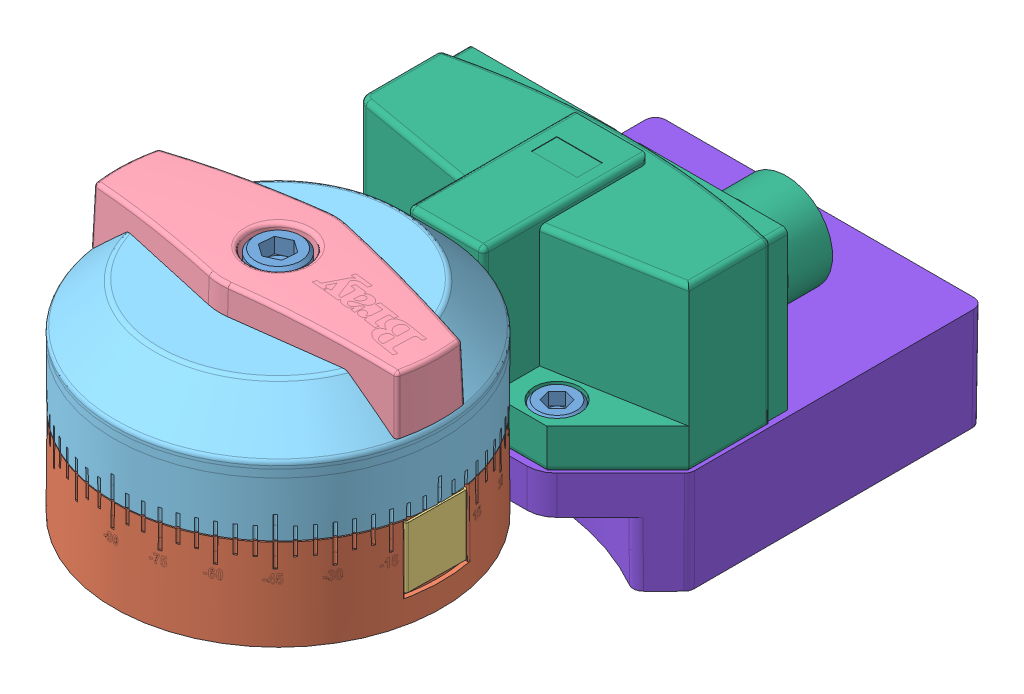
SolidWorks assembly SIZE 160-255, configuration Default. Lengths in mm.
Overall size (65.53 72.61 139.73).
13 component instances, 9 part files, 16 mates.
Components (placement in the parent):
- socket head cap screw_am-1: socket head cap screw_am [B18.3.1M - 5 x 0.8 x 12 Hex SHCS -- 12NHX] at (-500.171 31.6744 -463.7952) x (0 -1 0) z (-0.706848 0 0.707366) size (17 8.5 8.5)
- socket head cap screw_am-2: socket head cap screw_am [B18.3.1M - 5 x 0.8 x 12 Hex SHCS -- 12NHX] at (-470.1459 31.6744 -463.7952) x (0 -1 0) z (-0.706848 0 -0.707366) size (17 8.5 8.5)
- 54-000A-92510-1: 54-000A-92510 [Default] at (-485.1585 24.792 -423.7678) x (0.011705 0 -0.999931) z (0.999931 0 0.011705) size (64.81 35.64 64.77)
- 54-000A-73500-1: 54-000A-73500 [Default] at (-453.461 36.0489 -423.4339) x (0.011705 0 -0.999931) z (0.999931 0 0.011705) size (12.19 11.94 6.35)
- 54-000A-92512-1: 54-000A-92512 [Default] at (-485.1585 58.7518 -423.7678) x (-0.998952 0 -0.045767) z (0.045767 0 -0.998952) size (64.52 13.44 23.07)
- 54-000A-73500-2: 54-000A-73500 [Default] at (-484.8776 48.6153 -455.9616) x (-1 -0.000194 0.00096) z (-0.000958 -0.008727 -0.999961) size (12.19 11.94 6.35)
- 54-000A-92511-1: 54-000A-92511 [Default] at (-485.1585 42.8768 -423.7678) x (-0.999932 0 -0.011665) z (0.011665 0 -0.999932) size (64.76 21.97 66.01)
- 54-0004-71104-1: 54-0004-71104 [Default] at (-485.1732 23.6744 -492.2808) x (1 0 -0.000958) z (0.000958 0 1) size (65 33.5 50.77)
- 07-5623-72107-1: 07-5623-72107 [Default] at (-500.1471 20.3012 -488.7952) x (0 -1 0) z (0.643698 0 -0.76528) size (25 9.12 9.2)
- 07-5623-72107-2: 07-5623-72107 [Default] at (-470.1699 20.3012 -488.7952) x (0 -1 0) z (0.643698 0 0.76528) size (25 9.12 9.2)
- socket head cap screw_am-3: socket head cap screw_am [B18.3.1M - 6 x 1.0 x 30 Hex SHCS -- 30NHX] at (-485.1585 70.0858 -423.7678) x (0 -1 0) z (-0.995947 0 -0.089939) size (36 10 10)
- 54-160A-705S0-1: 54-160A-705S0 [Default] at (-485.2101 23.3696 -530.7098) x (-1 0 0.000958) z (-0.000958 0 -1) size (64.77 20.58 72.89)
- 54-160A-705P0-1: 54-160A-705P0 [Default] at (-485.1585 52.224 -423.7678) size (45.64 22.89 45.64)
Mates (geometry in assembly coordinates):
- Coincident1: coincident: plane of 54-000A-92510-1 through (-484.9073 52.224 -445.2293) normal (0 -1 0); plane of 54-160A-705P0-1 through (-485.1585 52.224 -423.7678) normal (0 1 0)
- Coincident2: coincident: plane of 54-000A-92510-1 through (-454.7314 24.792 -423.4117) normal (0.999931 0 0.011705); plane of 54-000A-73500-1 through (-454.6596 42.0179 -429.5444) normal (-0.999931 0 -0.011705)
- Parallel1: parallel: plane of 54-000A-73500-2 through (-478.7828 54.5853 -456.0195) normal (-0.000958 -0.008727 -0.999961); plane of 54-160A-705S0-1 through (-452.8251 23.3696 -530.7408) normal (-0.000958 -0.008727 -0.999961)
- Coincident3: coincident: line of 54-000A-73500-2 through (-490.9728 50.8497 -454.7052) axis (-0.000203 0.999962 -0.008726); plane of 54-000A-92511-1 through (-490.9626 42.8768 -454.2668) normal (0.99973 0 -0.023239)
- Coincident4: coincident: plane of 54-000A-92510-1 through (-485.0083 55.399 -436.5939) normal (0 1 0); plane of 54-000A-92511-1 through (-485.3053 55.399 -411.183) normal (0 -1 0)
- Parallel2: parallel: plane of 54-000A-92510-1 through (-454.8035 24.792 -417.2526) normal (0.046595 0 -0.998914); line of 54-000A-73500-1 through (-454.0657 30.0799 -417.3446) axis (0 1 0)
- Coincident5: coincident: plane of 54-000A-92512-1 through (-485.4102 64.0858 -418.2736) normal (0 1 0); plane of socket head cap screw_am-3 through (-485.6082 64.0858 -418.7881) normal (0 -1 0)
- Concentric1: concentric: cylinder of 54-000A-92510-1 through (-485.1585 15.4582 -423.7678) axis (0 1 0) radius 3.3; cylinder of 54-160A-705P0-1 through (-485.1585 61.5578 -423.7678) axis (0 -1 0) radius 3.3
- Concentric2: concentric: cylinder of 54-000A-92511-1 through (-485.1585 46.0652 -423.7678) axis (0 1 0) radius 3.3; cylinder of socket head cap screw_am-3 through (-485.1585 101.8358 -423.7678) axis (0 1 0) radius 3
- Concentric3: concentric: cylinder of 54-000A-92512-1 through (-485.1585 58.7518 -423.7678) axis (0 -1 0) radius 3.3; cylinder of 54-000A-92511-1 through (-485.1585 46.0652 -423.7678) axis (0 1 0) radius 3.3
- Distance1: distance = 0.1778 mm: plane of 54-000A-92511-1 through (-485.2755 58.574 -413.7355) normal (0 1 0); plane of 54-000A-92512-1 through (-485.4973 58.7518 -416.3715) normal (0 -1 0)
- Concentric4: concentric: circle of 07-5623-72107-2; circle of 54-160A-705S0-1
- Concentric5: concentric: circle of 07-5623-72107-2; circle of 54-160A-705S0-1
- Concentric6: concentric: cylinder of 54-000A-92510-1 through (-485.1585 15.4582 -423.7678) axis (0 1 0) radius 3.3; cylinder of 54-000A-92511-1 through (-485.1585 46.0652 -423.7678) axis (0 1 0) radius 3.3
- Concentric7: concentric: cylinder of 07-5623-72107-2 through (-470.1699 19.5012 -488.7952) axis (0 -1 0) radius 2.5; cylinder of 54-160A-705S0-1 through (-470.1699 23.3696 -488.7952) axis (0 1 0) radius 2.8067
- Concentric8: concentric: cone of 07-5623-72107-2 through (-470.1699 22.5512 -488.7952) axis (0 -1 0); cone of 54-160A-705S0-1 through (-470.1699 23.3696 -488.7952) axis (0 -1 0)
